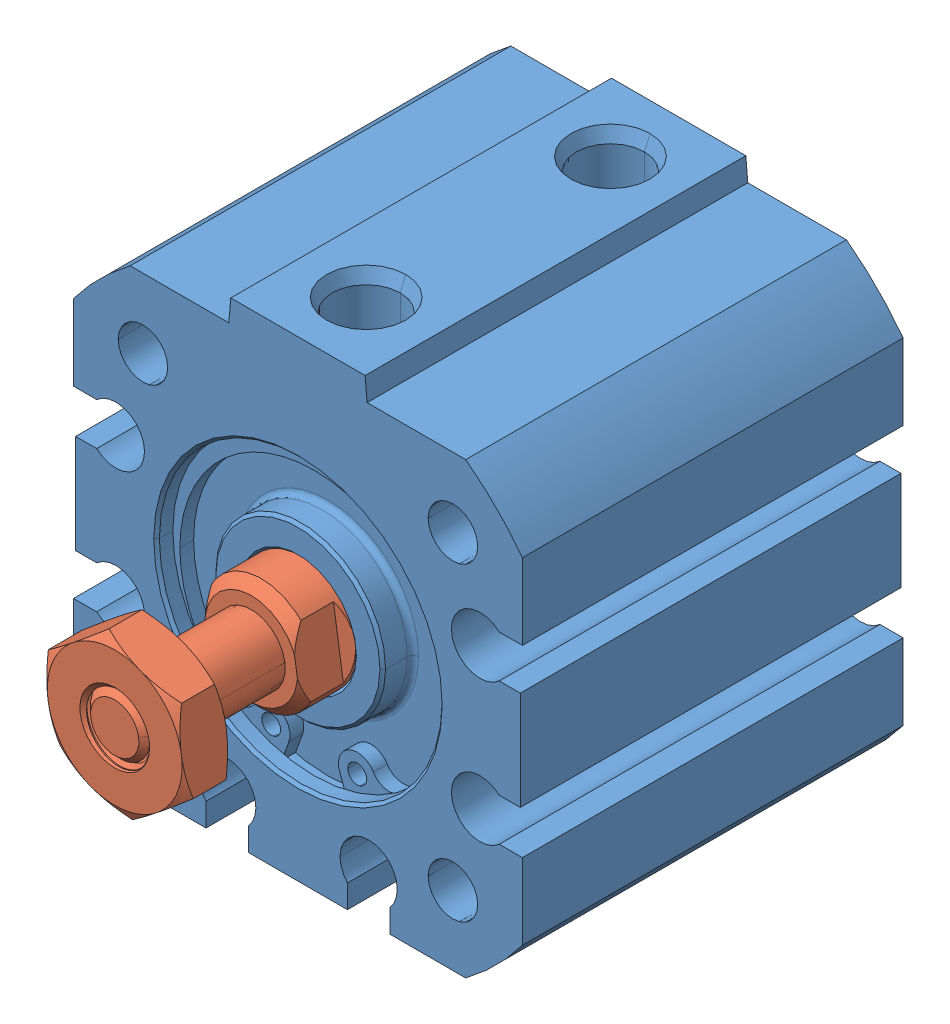
SolidWorks assembly Assem4, configuration Default. Lengths in mm.
Overall size (31.75 33.34 39.89).
2 component instances, 2 part files, 3 mates.
Components (placement in the parent):
- Pneumatic_Cylinder_body-1: Pneumatic_Cylinder_body [Default] at origin size (31.75 33.34 26.92)
- Pneumatic_Cylinder_pistion-1: Pneumatic_Cylinder_pistion [Default] x (-0.781407 -0.624021 0) z (0 0 1) size (18.95 18.95 35.28)
Mates (geometry in assembly coordinates):
- Coincident1: coordinate: point of Pneumatic_Cylinder_body-1
- Concentric1: concentric aligned: cylinder of Pneumatic_Cylinder_body-1 through (0 0 13.462) axis (0 0 -1) radius 3.937; cylinder of Pneumatic_Cylinder_pistion-1 through (0 0 27.99) axis (0 0 -1) radius 3.969
- LimitDistance1: limit distance = 0 mm anti-aligned: plane of Pneumatic_Cylinder_body-1 through (0 0 -8.85) normal (0 0 1); plane of Pneumatic_Cylinder_pistion-1 through (0 0 -8.85) normal (0 0 -1)
